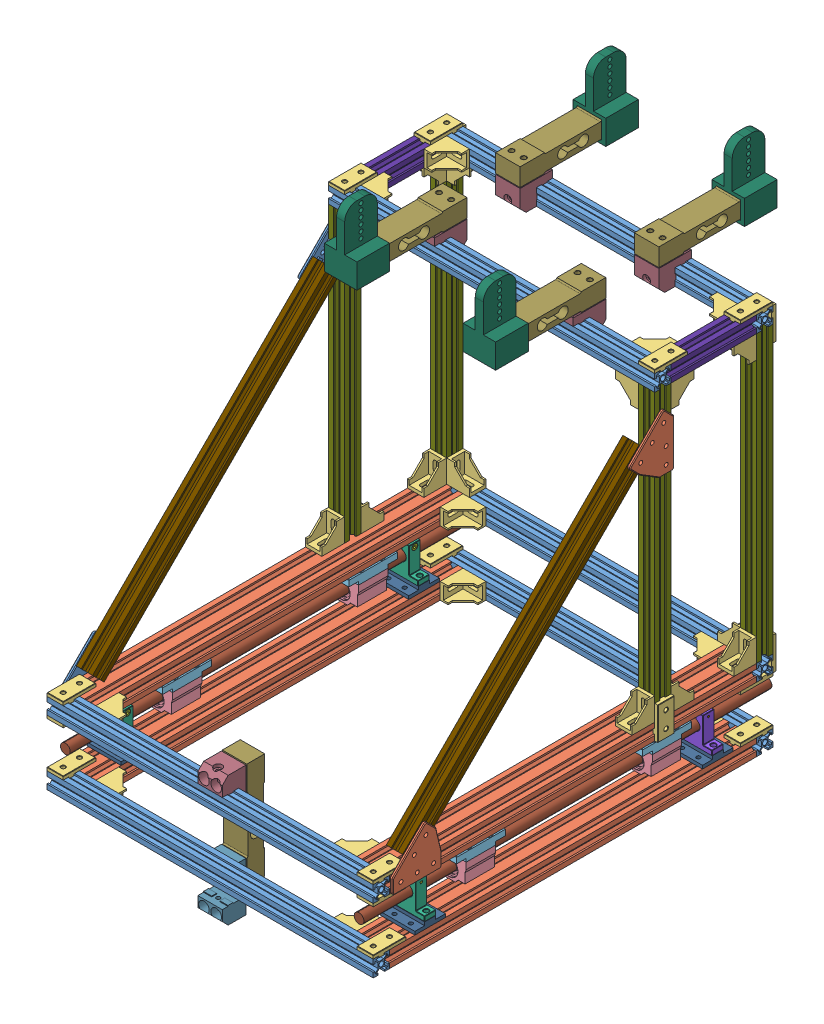
SolidWorks assembly Balança Final, configuration Default. Lengths in mm.
Overall size (408 595 590).
113 component instances, 21 part files, 135 mates.
Components (placement in the parent):
- Quadrado2040-1: Quadrado2040 [Default] at (-124.633 620.1559 -302.6488) x (1 0 0) z (0 -1 0) size (400 490 20)
  - 20x20x400_profile-4: 20x20x400_profile [Default] at (-5.8923 594.8177 297.0396) x (0 1 0) z (0 0 1) size (20 400 20)
  - 20x20x400_profile-5: 20x20x400_profile [Default] at (-405.8923 124.8177 297.0396) x (0 -1 0) z (0 0 1) size (20 400 20)
  - 20x40x450_profile-3: 20x40x450_profile [Default] at (-395.8923 134.8177 297.0396) size (40 450 20)
  - 20x40x450_profile-4: 20x40x450_profile [Default] at (-35.8923 134.8177 297.0396) size (40 450 20)
  - cantoneira_20x20-1: cantoneira_20x20 [Default] at (-45.8923 134.8177 307.0396) x (0 0 -1) z (1 0 0) size (20 28 28)
  - cantoneira_20x20-2: cantoneira_20x20 [Default] at (-45.8923 584.8177 307.0396) x (0 0 -1) z (0 1 0) size (20 28 28)
  - cantoneira_20x20-3: cantoneira_20x20 [Default] at (-365.8923 584.8177 307.0396) x (0 0 -1) z (-1 0 0) size (20 28 28)
  - cantoneira_20x20-4: cantoneira_20x20 [Default] at (-365.8923 134.8177 307.0396) x (0 0 -1) z (0 -1 0) size (20 28 28)
- Quadrado2040-2: Quadrado2040 [Default] at (-124.633 699.1559 -302.6488) x (1 0 0) z (0 -1 0) size (400 490 20)
  - 20x20x400_profile-4: 20x20x400_profile [Default] at (-5.8923 594.8177 297.0396) x (0 1 0) z (0 0 1) size (20 400 20)
  - 20x20x400_profile-5: 20x20x400_profile [Default] at (-405.8923 124.8177 297.0396) x (0 -1 0) z (0 0 1) size (20 400 20)
  - 20x40x450_profile-3: 20x40x450_profile [Default] at (-395.8923 134.8177 297.0396) size (40 450 20)
  - 20x40x450_profile-4: 20x40x450_profile [Default] at (-35.8923 134.8177 297.0396) size (40 450 20)
  - cantoneira_20x20-1: cantoneira_20x20 [Default] at (-45.8923 134.8177 307.0396) x (0 0 -1) z (1 0 0) size (20 28 28)
  - cantoneira_20x20-2: cantoneira_20x20 [Default] at (-45.8923 584.8177 307.0396) x (0 0 -1) z (0 1 0) size (20 28 28)
  - cantoneira_20x20-3: cantoneira_20x20 [Default] at (-365.8923 584.8177 307.0396) x (0 0 -1) z (-1 0 0) size (20 28 28)
  - cantoneira_20x20-4: cantoneira_20x20 [Default] at (-365.8923 134.8177 307.0396) x (0 0 -1) z (0 -1 0) size (20 28 28)
- SC12UU-4: SC12UU [Default] at (-510.5253 380.1163 171.1914) size (42 28 36)
- AdaptadorPillowBlock12-1: AdaptadorPillowBlock12 [Valor predeterminado] at (-510.5253 384.1163 171.1914) x (0 0 -1) z (1 0 0) size (60 12.59 42.39)
- SK12-5: SK12 [Valor predeterminado] at (-504.83 359.1 -160.831) size (42 37.6 14)
  - Shaft support SK12-1: Shaft support SK12 [Valor predeterminado] at (-5.6953 6.0163 42) size (42 37.5 14)
  - m4x16-2: m4x16 [Valor predeterminado] at (4.3047 16.0441 42) x (-1 0 0) z (0 0.924225 0.381849) size (20 7 7)
- EspelharSK12-10: EspelharSK12 [Valor predeterminado] at (-156.2206 359.1 -160.831) x (-1 0 0) z (0 0 -1) size (42 37.6 14)
  - EspelharShaft support SK12-1: EspelharShaft support SK12 [Valor predeterminado] at (-5.6953 6.0163 -42) size (42 37.5 14)
  - Espelharm4x16-1: Espelharm4x16 [Valor predeterminado] at (4.3047 16.0441 -42) x (-1 0 0) z (0 -0.924225 0.381849) size (20 7 7)
- SK12-9: SK12 [Valor predeterminado] at (-504.83 359.1 191.169) size (42 37.6 14)
  - Shaft support SK12-1: Shaft support SK12 [Valor predeterminado] at (-5.6953 6.0163 42) size (42 37.5 14)
  - m4x16-2: m4x16 [Valor predeterminado] at (4.3047 16.0441 42) x (-1 0 0) z (0 0.924225 0.381849) size (20 7 7)
- SK12-11: SK12 [Valor predeterminado] at (-156.2206 359.1 275.169) x (-1 0 0) z (0 0 -1) size (42 37.6 14)
  - Shaft support SK12-1: Shaft support SK12 [Valor predeterminado] at (-5.6953 6.0163 42) size (42 37.5 14)
  - m4x16-2: m4x16 [Valor predeterminado] at (4.3047 16.0441 42) x (-1 0 0) z (0 0.924225 0.381849) size (20 7 7)
- AdaptadorSuporteSK12-1: AdaptadorSuporteSK12 [Valor predeterminado] at (-510.5253 333.1163 -119.081) x (0 0 1) z (-1 0 0) size (37.5 9 42)
- EixoLinear12x500mm-1: EixoLinear12x500mm [Default] at (-510.5253 365.1163 49.5418) x (-0.052176 0.998638 0) z (0 0 1) size (12 12 500)
- EixoLinear12x500mm-2: EixoLinear12x500mm [Default] at (-150.5253 365.1163 49.5418) x (0.95426 0.298977 0) z (0 0 1) size (12 12 500)
- load_cell_big_20kg-9: load_cell_big_20kg [Default] at (-430.5253 803.1163 -212.831) size (30 22 130)
- load_cell_big_20kg-10: load_cell_big_20kg [Default] at (-430.5253 803.1163 -17.831) size (30 22 130)
- SuporteCelulaCarga_Reforcado-1: SuporteCelulaCarga_Reforcado [Valor predeterminado] at (-430.5253 779.361 -166.5879) size (30 30 40)
- SuporteCelulaCarga_Reforcado-2: SuporteCelulaCarga_Reforcado [Valor predeterminado] at (-400.5253 779.361 -64.0742) x (-1 0 0) z (0 0 -1) size (30 30 40)
- SuporteCelulaCarga_Reforcado-6: SuporteCelulaCarga_Reforcado [Valor predeterminado] at (-345.5253 413.3595 284.9243) x (1 0 0) z (0 1 0) size (30 30 40)
- load_cell_big_20kg-1: load_cell_big_20kg [Default] at (-345.5253 367.6163 261.169) x (1 0 0) z (0 -1 0) size (30 22 130)
- SuporteCelulaCarga_Reforcado_Ajustavel-1: SuporteCelulaCarga_Reforcado_Ajustavel [Valor predeterminado] at (-315.5253 291.8731 284.9243) x (-1 0 0) z (0 -1 0) size (30 30 60)
- EncaixeAsaTraseiro_Alt3-1: EncaixeAsaTraseiro_Alt3 [Default] at (-415.5253 788.1163 37.169) size (40 80 40)
- EncaixeAsaTraseiro_Alt3-2: EncaixeAsaTraseiro_Alt3 [Default] at (-415.5253 788.1163 -267.831) x (-1 0 0) z (0 0 -1) size (40 80 40)
- load_cell_big_20kg-11: load_cell_big_20kg [Default] at (-230.5253 803.1163 -212.831) x (-1 0 0) z (0 0 -1) size (30 22 130)
- load_cell_big_20kg-12: load_cell_big_20kg [Default] at (-230.5253 803.1163 -17.831) x (-1 0 0) z (0 0 -1) size (30 22 130)
- EncaixeAsaTraseiro_Alt3-3: EncaixeAsaTraseiro_Alt3 [Default] at (-245.5253 788.1163 -267.831) x (-1 0 0) z (0 0 -1) size (40 80 40)
- EncaixeAsaTraseiro_Alt3-4: EncaixeAsaTraseiro_Alt3 [Default] at (-245.5253 788.1163 37.169) size (40 80 40)
- cantoneira_20x20-1: cantoneira_20x20 [Default] at (-510.5253 412.1163 -167.831) x (-1 0 0) z (0 0 -1) size (20 28 28)
- cantoneira_20x20-2: cantoneira_20x20 [Default] at (-510.5253 412.1163 -187.831) x (0 0 1) z (-1 0 0) size (20 28 28)
- cantoneira_20x20-4: cantoneira_20x20 [Default] at (-530.5253 762.1163 -167.831) x (1 0 0) z (0 0 -1) size (20 28 28)
- cantoneira_20x20-5: cantoneira_20x20 [Default] at (-510.5253 762.1163 -167.831) x (0 0 -1) z (-1 0 0) size (20 28 28)
- cantoneira_20x20-6: cantoneira_20x20 [Default] at (-510.5253 762.1163 -167.831) x (0 1 0) z (0 0 -1) size (20 28 28)
- cantoneira_20x20-7: cantoneira_20x20 [Default] at (-510.5253 762.1163 -62.831) x (0 1 0) z (-1 0 0) size (20 28 28)
- cantoneira_20x20-15: cantoneira_20x20 [Default] at (-530.5253 762.1163 -62.831) x (1 0 0) z (0 1 0) size (20 28 28)
- cantoneira_20x20-16: cantoneira_20x20 [Default] at (-510.5253 762.1163 -42.831) x (0 0 -1) z (-1 0 0) size (20 28 28)
- cantoneira_20x20-21: cantoneira_20x20 [Default] at (-530.5253 412.1163 -62.831) size (20 28 28)
- cantoneira_20x20-23: cantoneira_20x20 [Default] at (-530.5253 412.1163 -42.831) x (1 0 0) z (0 -1 0) size (20 28 28)
- cantoneira_20x20-8: cantoneira_20x20 [Default] at (-130.5253 412.1163 -167.831) x (-1 0 0) z (0 0 -1) size (20 28 28)
- cantoneira_20x20-10: cantoneira_20x20 [Default] at (-150.5253 412.1163 -167.831) x (0 0 -1) z (1 0 0) size (20 28 28)
- cantoneira_20x20-11: cantoneira_20x20 [Default] at (-150.5253 782.1163 -167.831) x (0 -1 0) z (0 0 -1) size (20 28 28)
- cantoneira_20x20-12: cantoneira_20x20 [Default] at (-150.5253 762.1163 -187.831) x (0 0 1) z (1 0 0) size (20 28 28)
- cantoneira_20x20-13: cantoneira_20x20 [Default] at (-150.5253 762.1163 -167.831) x (1 0 0) z (0 0 -1) size (20 28 28)
- cantoneira_20x20-14: cantoneira_20x20 [Default] at (-150.5253 782.1163 -62.831) x (0 -1 0) z (1 0 0) size (20 28 28)
- 20x20x350_profile-7: 20x20x350_profile [Default] at (-520.5253 412.1163 -177.831) size (20 350 20)
- 20x20x350_profile-8: 20x20x350_profile [Default] at (-140.5253 412.1163 -177.831) x (-1 0 0) z (0 0 -1) size (20 350 20)
- 20x20x105_profile-1: 20x20x105_profile [Default] at (-520.5253 772.1163 -167.831) x (1 0 0) z (0 -1 0) size (20 105 20)
- 20x20x105_profile-2: 20x20x105_profile [Default] at (-140.5253 772.1163 -167.831) x (-1 0 0) z (0 1 0) size (20 105 20)
- 20x20x410_profile-1: 20x20x410_profile [Default] at (-520.5253 427.7919 250.4913) x (1 0 0) z (0 0.707107 0.707107) size (20 410 20)
- 20x20x410_profile-2: 20x20x410_profile [Default] at (-140.5253 427.7919 250.4913) x (-1 0 0) z (0 -0.707107 -0.707107) size (20 410 20)
- 20x20x400_profile-1: 20x20x400_profile [Default] at (-130.5253 772.1163 -177.831) x (0 1 0) z (0 0 1) size (20 400 20)
- 20x20x400_profile-2: 20x20x400_profile [Default] at (-130.5253 772.1163 -52.831) x (0 1 0) z (0 0 1) size (20 400 20)
- 20x20x350_profile-9: 20x20x350_profile [Default] at (-520.5253 412.1163 -52.831) size (20 350 20)
- SC12UU-5: SC12UU [Default] at (-510.5253 380.1163 -56.8535) size (42 28 36)
- SC12UU-6: SC12UU [Default] at (-150.5253 380.1163 171.1914) x (-1 0 0) z (0 0 -1) size (42 28 36)
- SC12UU-7: SC12UU [Default] at (-150.5253 380.1163 -56.8535) x (-1 0 0) z (0 0 -1) size (42 28 36)
- AdaptadorPillowBlock12-2: AdaptadorPillowBlock12 [Valor predeterminado] at (-510.5253 384.1163 -56.8535) x (0 0 1) z (-1 0 0) size (60 12.59 42.39)
- AdaptadorPillowBlock12-3: AdaptadorPillowBlock12 [Valor predeterminado] at (-150.5253 384.1163 171.1914) x (0 0 -1) z (1 0 0) size (60 12.59 42.39)
- AdaptadorPillowBlock12-4: AdaptadorPillowBlock12 [Valor predeterminado] at (-150.5253 384.1163 -56.8535) x (0 0 1) z (-1 0 0) size (60 12.59 42.39)
- AdaptadorSuporteSK12-2: AdaptadorSuporteSK12 [Valor predeterminado] at (-510.5253 333.1163 233.419) x (0 0 -1) z (1 0 0) size (37.5 9 42)
- AdaptadorSuporteSK12-3: AdaptadorSuporteSK12 [Valor predeterminado] at (-150.5253 333.1163 -119.081) x (0 0 1) z (-1 0 0) size (37.5 9 42)
- AdaptadorSuporteSK12-4: AdaptadorSuporteSK12 [Valor predeterminado] at (-150.5253 333.1163 233.419) x (0 0 -1) z (1 0 0) size (37.5 9 42)
- SuporteCelulaCarga_Reforcado-3: SuporteCelulaCarga_Reforcado [Valor predeterminado] at (-260.5253 779.361 -166.5879) size (30 30 40)
- SuporteCelulaCarga_Reforcado-4: SuporteCelulaCarga_Reforcado [Valor predeterminado] at (-230.5253 779.361 -64.0742) x (-1 0 0) z (0 0 -1) size (30 30 40)
- Placa_lateral_45_esq-1: Placa_lateral_45_esq [Default] at (-530.5253 392.1163 300.3091) x (-1 0 0) z (0 0 -1) size (6 57.44 60)
- Placa_lateral_45_esq-2: Placa_lateral_45_esq [Default] at (-530.5253 755.2564 -62.831) x (-1 0 0) z (0 -0.707107 0.707107) size (6 57.44 60)
- Placa_lateral_45_dir-1: Placa_lateral_45_dir [Default] at (-126.5253 392.1163 300.3091) x (-1 0 0) z (0 0 -1) size (6 57.44 60)
- Placa_lateral_45_dir-2: Placa_lateral_45_dir [Default] at (-126.5253 755.2564 -62.831) x (-1 0 0) z (0 -0.707107 0.707107) size (6 57.44 60)
- Cantoneira_plana-1: Cantoneira_plana [Valor predeterminado] at (-520.5253 762.1163 -187.831) x (1 0 0) z (0 1 0) size (20 6 40)
- Cantoneira_plana-2: Cantoneira_plana [Valor predeterminado] at (-520.5253 782.1163 -167.831) x (-1 0 0) z (0 0 -1) size (20 6 40)
- Cantoneira_plana-4: Cantoneira_plana [Valor predeterminado] at (-520.5253 412.1163 -187.831) x (-1 0 0) z (0 -1 0) size (20 6 40)
- Cantoneira_plana-5: Cantoneira_plana [Valor predeterminado] at (-520.5253 392.1163 -167.831) x (1 0 0) z (0 0 -1) size (20 6 40)
- Cantoneira_plana-6: Cantoneira_plana [Valor predeterminado] at (-520.5253 392.1163 282.169) x (-1 0 0) z (0 0 1) size (20 6 40)
- Cantoneira_plana-12: Cantoneira_plana [Valor predeterminado] at (-520.5253 782.1163 -62.831) size (20 6 40)
- Cantoneira_plana-14: Cantoneira_plana [Valor predeterminado] at (-520.5253 412.1163 282.169) size (20 6 40)
- Cantoneira_plana-18: Cantoneira_plana [Valor predeterminado] at (-520.5253 333.1163 -167.831) x (-1 0 0) z (0 0 -1) size (20 6 40)
- Cantoneira_plana-19: Cantoneira_plana [Valor predeterminado] at (-520.5253 333.1163 282.169) size (20 6 40)
- Cantoneira_plana-22: Cantoneira_plana [Valor predeterminado] at (-530.5253 412.1163 -52.831) x (0 0 1) z (0 -1 0) size (20 6 40)
- Cantoneira_plana-7: Cantoneira_plana [Valor predeterminado] at (-140.5253 392.1163 -167.831) x (1 0 0) z (0 0 -1) size (20 6 40)
- Cantoneira_plana-8: Cantoneira_plana [Valor predeterminado] at (-140.5253 412.1163 -187.831) x (-1 0 0) z (0 -1 0) size (20 6 40)
- Cantoneira_plana-9: Cantoneira_plana [Valor predeterminado] at (-140.5253 392.1163 282.169) x (-1 0 0) z (0 0 1) size (20 6 40)
- Cantoneira_plana-10: Cantoneira_plana [Valor predeterminado] at (-140.5253 762.1163 -187.831) x (1 0 0) z (0 1 0) size (20 6 40)
- Cantoneira_plana-11: Cantoneira_plana [Valor predeterminado] at (-140.5253 782.1163 -167.831) x (-1 0 0) z (0 0 -1) size (20 6 40)
- Cantoneira_plana-13: Cantoneira_plana [Valor predeterminado] at (-140.5253 782.1163 -62.831) size (20 6 40)
- Cantoneira_plana-15: Cantoneira_plana [Valor predeterminado] at (-140.5253 412.1163 282.169) size (20 6 40)
- Cantoneira_plana-20: Cantoneira_plana [Valor predeterminado] at (-140.5253 333.1163 -167.831) x (-1 0 0) z (0 0 -1) size (20 6 40)
- Cantoneira_plana-21: Cantoneira_plana [Valor predeterminado] at (-140.5253 333.1163 282.169) size (20 6 40)
- cantoneira_20x20-19: cantoneira_20x20 [Default] at (-150.5253 762.1163 -62.831) x (1 0 0) z (0 1 0) size (20 28 28)
- cantoneira_20x20-20: cantoneira_20x20 [Default] at (-150.5253 762.1163 -62.831) x (0 0 1) z (1 0 0) size (20 28 28)
- cantoneira_20x20-22: cantoneira_20x20 [Default] at (-150.5253 412.1163 -62.831) size (20 28 28)
- cantoneira_20x20-24: cantoneira_20x20 [Default] at (-150.5253 412.1163 -42.831) x (1 0 0) z (0 -1 0) size (20 28 28)
- 20x20x350_profile-11: 20x20x350_profile [Default] at (-140.5253 412.1163 -52.831) x (-1 0 0) z (0 0 -1) size (20 350 20)
- Cantoneira_plana-24: Cantoneira_plana [Valor predeterminado] at (-130.5253 412.1163 -52.831) x (0 0 -1) z (0 -1 0) size (20 6 40)
Mates (geometry in assembly coordinates):
- Concentric1: concentric anti-aligned: cylinder of SK12-9/Shaft support SK12-1 through (-510.5253 365.1163 226.169) axis (0 0 1) radius 6; cylinder of EixoLinear12x500mm-1 through (-510.5253 365.1163 299.5418) axis (0 0 -1) radius 6
- Concentric2: concentric aligned: cylinder of ? through (-150.5253 356.1163 -143.831) axis (0 0 -1) radius 6; cylinder of EixoLinear12x500mm-2 through (-150.5253 356.1163 312.6848) axis (0 0 -1) radius 6
- Concentric4: concentric anti-aligned: cylinder of EixoLinear12x500mm-1 through (-510.5253 365.1163 299.5418) axis (0 0 -1) radius 6; cylinder of SC12UU-4 through (-510.5253 365.1163 201.4668) axis (0 0 1) radius 6
- Coincident15: coincident aligned: plane of Quadrado2040-1/20x20x400_profile-4 through (-530.5253 319.1163 302.169) normal (0 0 1); plane of Quadrado2040-2/20x20x400_profile-4 through (-530.5253 398.1163 302.169) normal (0 0 1)
- Coincident16: coincident aligned: plane of Quadrado2040-1/20x40x450_profile-3 through (-530.5253 333.1163 282.169) normal (-1 0 0); plane of Quadrado2040-2/20x40x450_profile-3 through (-530.5253 412.1163 282.169) normal (-1 0 0)
- Width6: width anti-aligned: plane of load_cell_big_20kg-1 through (-345.5253 367.6163 261.169) normal (-1 0 0); plane of load_cell_big_20kg-1 through (-315.5253 367.6163 261.169) normal (1 0 0); plane of Quadrado2040-2/20x20x400_profile-4 through (-130.5253 402.1163 292.169) normal (1 0 0); plane of Quadrado2040-2/20x20x400_profile-4 through (-530.5253 402.1163 292.169) normal (-1 0 0)
- Coincident124: coincident aligned: plane of 20x20x350_profile-7 through (-530.5253 762.1163 -173.831) normal (-1 0 0); plane of 20x20x105_profile-1 through (-530.5253 782.1163 -62.831) normal (-1 0 0)
- Coincident133: coincident aligned: plane of 20x20x105_profile-1 through (-530.5253 768.1163 -62.831) normal (-1 0 0); plane of 20x20x410_profile-1 through (-530.5253 702.0301 -37.889) normal (-1 0 0)
- Coincident145: coincident anti-aligned: plane of load_cell_big_20kg-10 through (-400.5253 803.1163 47.169) normal (0 0 1); plane of EncaixeAsaTraseiro_Alt3-1 through (-415.5253 788.1163 47.169) normal (0 0 -1)
- Coincident146: coincident anti-aligned: plane of load_cell_big_20kg-10 through (-400.5253 803.1163 -17.831) normal (1 0 0); plane of EncaixeAsaTraseiro_Alt3-1 through (-400.5253 814.1163 47.169) normal (-1 0 0)
- Coincident147: coincident anti-aligned: plane of load_cell_big_20kg-10 through (-400.5253 792.1163 -17.831) normal (0 -1 0); plane of EncaixeAsaTraseiro_Alt3-1 through (-400.5253 792.1163 47.169) normal (0 1 0)
- Coincident150: coincident anti-aligned: plane of load_cell_big_20kg-9 through (-400.5253 792.1163 -212.831) normal (0 -1 0); plane of EncaixeAsaTraseiro_Alt3-2 through (-430.5253 792.1163 -277.831) normal (0 1 0)
- Coincident151: coincident anti-aligned: plane of load_cell_big_20kg-9 through (-400.5253 803.1163 -277.831) normal (0 0 -1); plane of EncaixeAsaTraseiro_Alt3-2 through (-415.5253 788.1163 -277.831) normal (0 0 1)
- Coincident152: coincident anti-aligned: plane of load_cell_big_20kg-9 through (-430.5253 803.1163 -212.831) normal (-1 0 0); plane of EncaixeAsaTraseiro_Alt3-2 through (-430.5253 814.1163 -277.831) normal (1 0 0)
- Coincident174: coincident anti-aligned: plane of Quadrado2040-2/20x20x400_profile-5 through (-130.5253 412.1163 -167.831) normal (0 1 0); plane of 20x20x350_profile-7 through (-520.5253 412.1163 -177.831) normal (0 -1 0)
- Coincident178: coincident aligned: plane of Quadrado2040-2/20x20x400_profile-5 through (-130.5253 398.1163 -187.831) normal (0 0 -1); plane of 20x20x350_profile-8 through (-130.5253 762.1163 -187.831) normal (0 0 -1)
- Coincident194: coincident aligned: plane of EixoLinear12x500mm-1 through (-510.5253 365.1163 -200.4582) normal (0 0 -1); plane of EixoLinear12x500mm-2 through (-150.5253 365.1163 -200.4582) normal (0 0 -1)
- Coincident197: coincident: plane of Quadrado2040-2/20x40x450_profile-3 through (-530.5253 412.1163 282.169) normal (0 1 0); line of 20x20x410_profile-1 through (-530.5253 412.1163 252.0248) axis (1 0 0)
- Coincident199: coincident anti-aligned: plane of Quadrado2040-2/20x40x450_profile-3 through (-530.5253 412.1163 282.169) normal (0 1 0); plane of cantoneira_20x20-1 through (-530.5253 412.1163 -167.831) normal (0 -1 0)
- Coincident200: coincident aligned: plane of Quadrado2040-2/20x40x450_profile-3 through (-530.5253 412.1163 282.169) normal (-1 0 0); plane of cantoneira_20x20-1 through (-530.5253 412.1163 -167.831) normal (-1 0 0)
- Coincident201: coincident anti-aligned: plane of 20x20x350_profile-7 through (-530.5253 762.1163 -167.831) normal (0 0 1); plane of cantoneira_20x20-1 through (-530.5253 412.1163 -167.831) normal (0 0 -1)
- Coincident202: coincident anti-aligned: plane of 20x20x350_profile-7 through (-510.5253 762.1163 -187.831) normal (1 0 0); plane of cantoneira_20x20-2 through (-510.5253 412.1163 -167.831) normal (-1 0 0)
- Coincident203: coincident anti-aligned: plane of Quadrado2040-2/20x20x400_profile-5 through (-130.5253 412.1163 -181.831) normal (0 1 0); plane of cantoneira_20x20-2 through (-510.5253 412.1163 -167.831) normal (0 -1 0)
- Coincident204: coincident aligned: plane of Quadrado2040-2/20x20x400_profile-5 through (-130.5253 412.1163 -187.831) normal (0 0 -1); plane of cantoneira_20x20-2 through (-510.5253 412.1163 -187.831) normal (0 0 -1)
- Coincident211: coincident anti-aligned: plane of 20x20x105_profile-1 through (-510.5253 782.1163 -62.831) normal (1 0 0); plane of cantoneira_20x20-6 through (-510.5253 782.1163 -167.831) normal (-1 0 0)
- Coincident213: coincident aligned: plane of 20x20x105_profile-1 through (-530.5253 768.1163 -62.831) normal (-1 0 0); plane of cantoneira_20x20-4 through (-530.5253 762.1163 -167.831) normal (-1 0 0)
- Coincident214: coincident anti-aligned: plane of 20x20x350_profile-7 through (-530.5253 762.1163 -167.831) normal (0 0 1); plane of cantoneira_20x20-4 through (-510.5253 762.1163 -167.831) normal (0 0 -1)
- Coincident215: coincident anti-aligned: plane of 20x20x105_profile-1 through (-530.5253 762.1163 -62.831) normal (0 -1 0); plane of cantoneira_20x20-4 through (-510.5253 762.1163 -167.831) normal (0 1 0)
- Coincident216: coincident anti-aligned: plane of 20x20x350_profile-7 through (-510.5253 762.1163 -173.831) normal (1 0 0); plane of cantoneira_20x20-5 through (-510.5253 762.1163 -187.831) normal (-1 0 0)
- Coincident220: coincident anti-aligned: plane of 20x20x105_profile-1 through (-510.5253 782.1163 -62.831) normal (1 0 0); plane of cantoneira_20x20-7 through (-510.5253 782.1163 -62.831) normal (-1 0 0)
- Coincident222: coincident aligned: plane of 20x20x105_profile-1 through (-516.5253 782.1163 -62.831) normal (0 1 0); plane of cantoneira_20x20-7 through (-510.5253 782.1163 -62.831) normal (0 1 0)
- Coincidente1: coincident aligned: plane of 20x20x350_profile-7 through (-530.5253 762.1163 -187.831) normal (-1 0 0); plane of 20x20x400_profile-1 through (-530.5253 772.1163 -177.831) normal (-1 0 0)
- Coincidente2: coincident aligned: plane of 20x20x350_profile-7 through (-516.5253 762.1163 -187.831) normal (0 0 -1); plane of 20x20x400_profile-1 through (-530.5253 776.1163 -187.831) normal (0 0 -1)
- Coincidente3: coincident anti-aligned: plane of 20x20x350_profile-7 through (-520.5253 762.1163 -177.831) normal (0 1 0); plane of 20x20x400_profile-1 through (-530.5253 762.1163 -187.831) normal (0 -1 0)
- Coincidente4: coincident anti-aligned: plane of 20x20x105_profile-1 through (-520.5253 772.1163 -167.831) normal (0 0 -1); plane of 20x20x400_profile-1 through (-530.5253 776.1163 -167.831) normal (0 0 1)
- Coincidente7: coincident aligned: plane of 20x20x105_profile-1 through (-530.5253 782.1163 -62.831) normal (-1 0 0); plane of 20x20x400_profile-2 through (-530.5253 772.1163 -52.831) normal (-1 0 0)
- Coincidente8: coincident aligned: plane of 20x20x105_profile-1 through (-516.5253 782.1163 -62.831) normal (0 1 0); plane of 20x20x400_profile-2 through (-530.5253 782.1163 -62.831) normal (0 1 0)
- Coincidente9: coincident aligned: plane of 20x20x105_profile-1 through (-516.5253 782.1163 -62.831) normal (0 1 0); plane of 20x20x400_profile-1 through (-530.5253 782.1163 -173.831) normal (0 1 0)
- Coincidente10: coincident anti-aligned: plane of 20x20x105_profile-1 through (-520.5253 772.1163 -62.831) normal (0 0 1); plane of 20x20x400_profile-2 through (-530.5253 762.1163 -62.831) normal (0 0 -1)
- Distância1: distance = 100 mm aligned: plane of load_cell_big_20kg-9 through (-430.5253 803.1163 -212.831) normal (-1 0 0); plane of 20x20x400_profile-1 through (-530.5253 772.1163 -177.831) normal (-1 0 0)
- Coincidente21: coincident aligned: plane of load_cell_big_20kg-9 through (-430.5253 803.1163 -212.831) normal (-1 0 0); plane of load_cell_big_20kg-10 through (-430.5253 803.1163 -17.831) normal (-1 0 0)
- Concêntrico1: concentric anti-aligned: cylinder of EspelharSK12-10/EspelharShaft support SK12-1 through (-150.5253 365.1163 -125.831) axis (0 0 1) radius 6; cylinder of EixoLinear12x500mm-2 through (-150.5253 365.1163 299.5418) axis (0 0 -1) radius 6
- Coincidente22: coincident anti-aligned: plane of Quadrado2040-2/20x40x450_profile-3 through (-516.5253 392.1163 282.169) normal (0 -1 0); plane of AdaptadorPillowBlock12-1 through (-510.5253 392.1163 171.1914) normal (0 1 0)
- Coincidente23: coincident anti-aligned: plane of SC12UU-4 through (-521.5253 380.1163 189.1914) normal (0 1 0); plane of AdaptadorPillowBlock12-1 through (-510.5253 380.1163 171.1914) normal (0 -1 0)
- Coincidente24: coincident aligned: plane of SC12UU-4 through (-531.5253 380.1163 189.1914) normal (-1 0 0); plane of AdaptadorPillowBlock12-1 through (-531.5253 392.1163 171.1914) normal (-1 0 0)
- Coincidente25: coincident aligned: plane of SC12UU-4 through (-510.5253 380.1163 153.1914) normal (0 0 -1); plane of AdaptadorPillowBlock12-1 through (-510.5253 380.1163 153.1914) normal (0 0 -1)
- Distância2: distance = 1 mm aligned: plane of AdaptadorPillowBlock12-1 through (-531.5253 392.1163 171.1914) normal (-1 0 0); plane of Quadrado2040-2/20x40x450_profile-3 through (-530.5253 398.1163 282.169) normal (-1 0 0)
- Concêntrico2: concentric anti-aligned: cylinder of SK12-5/Shaft support SK12-1 through (-510.5253 365.1163 -125.831) axis (0 0 1) radius 6; cylinder of EixoLinear12x500mm-1 through (-510.5253 365.1163 299.5418) axis (0 0 -1) radius 6
- Coincidente32: coincident anti-aligned: plane of cantoneira_20x20-5 through (-510.5253 762.1163 -187.831) normal (0 1 0); plane of 20x20x400_profile-1 through (-530.5253 762.1163 -187.831) normal (0 -1 0)
- Coincidente33: coincident aligned: plane of cantoneira_20x20-5 through (-510.5253 762.1163 -187.831) normal (0 0 -1); plane of 20x20x400_profile-1 through (-530.5253 762.1163 -187.831) normal (0 0 -1)
- Coincidente34: coincident anti-aligned: plane of 20x20x105_profile-1 through (-510.5253 782.1163 -62.831) normal (1 0 0); plane of cantoneira_20x20-6 through (-510.5253 782.1163 -167.831) normal (-1 0 0)
- Coincidente35: coincident aligned: plane of cantoneira_20x20-6 through (-510.5253 782.1163 -167.831) normal (0 1 0); plane of 20x20x400_profile-1 through (-530.5253 782.1163 -173.831) normal (0 1 0)
- Coincidente36: coincident anti-aligned: plane of cantoneira_20x20-6 through (-510.5253 782.1163 -167.831) normal (0 0 -1); plane of 20x20x400_profile-1 through (-530.5253 776.1163 -167.831) normal (0 0 1)
- Coincidente37: coincident anti-aligned: plane of Quadrado2040-1/20x40x450_profile-3 through (-530.5253 333.1163 282.169) normal (0 1 0); plane of AdaptadorSuporteSK12-1 through (-510.5253 333.1163 -119.081) normal (0 -1 0)
- Coincidente40: coincident anti-aligned: plane of SK12-5/Shaft support SK12-1 through (-510.5253 342.1163 -125.831) normal (0 -1 0); plane of AdaptadorSuporteSK12-1 through (-510.5253 342.1163 -119.081) normal (0 1 0)
- Coincidente41: coincident aligned: plane of SK12-5/Shaft support SK12-1 through (-510.5253 316.9299 -125.831) normal (0 0 -1); plane of AdaptadorSuporteSK12-1 through (-510.5253 342.1163 -125.831) normal (0 0 -1)
- Coincidente42: coincident aligned: plane of SK12-5/Shaft support SK12-1 through (-531.5253 316.9299 -125.831) normal (-1 0 0); plane of AdaptadorSuporteSK12-1 through (-531.5253 338.1163 -119.081) normal (-1 0 0)
- Coincidente44: coincident anti-aligned: plane of 20x20x400_profile-1 through (-530.5253 782.1163 -173.831) normal (0 1 0); plane of SuporteCelulaCarga_Reforcado-1 through (-400.5253 782.1163 -166.5879) normal (0 -1 0)
- Coincidente45: coincident anti-aligned: plane of 20x20x400_profile-1 through (-530.5253 776.1163 -167.831) normal (0 0 1); plane of SuporteCelulaCarga_Reforcado-1 through (-400.5253 779.361 -167.831) normal (0 0 -1)
- Coincidente46: coincident aligned: plane of load_cell_big_20kg-9 through (-400.5253 803.1163 -147.831) normal (0 0 1); plane of SuporteCelulaCarga_Reforcado-1 through (-400.5253 779.361 -147.831) normal (0 0 1)
- Coincidente47: coincident anti-aligned: plane of load_cell_big_20kg-9 through (-400.5253 792.1163 -212.831) normal (0 -1 0); plane of SuporteCelulaCarga_Reforcado-1 through (-400.5253 792.1163 -166.5879) normal (0 1 0)
- Coincidente48: coincident aligned: plane of load_cell_big_20kg-9 through (-430.5253 803.1163 -212.831) normal (-1 0 0); plane of SuporteCelulaCarga_Reforcado-1 through (-430.5253 779.361 -166.5879) normal (-1 0 0)
- Coincidente49: coincident anti-aligned: plane of 20x20x400_profile-2 through (-530.5253 782.1163 -48.831) normal (0 1 0); plane of SuporteCelulaCarga_Reforcado-2 through (-430.5253 782.1163 -64.0742) normal (0 -1 0)
- Coincidente50: coincident anti-aligned: plane of 20x20x400_profile-2 through (-530.5253 776.1163 -62.831) normal (0 0 -1); plane of SuporteCelulaCarga_Reforcado-2 through (-430.5253 779.361 -62.831) normal (0 0 1)
- Coincidente51: coincident aligned: plane of load_cell_big_20kg-10 through (-430.5253 803.1163 -17.831) normal (-1 0 0); plane of SuporteCelulaCarga_Reforcado-2 through (-430.5253 779.361 -64.0742) normal (-1 0 0)
- Coincidente52: coincident aligned: plane of load_cell_big_20kg-10 through (-400.5253 803.1163 -82.831) normal (0 0 -1); plane of SuporteCelulaCarga_Reforcado-2 through (-430.5253 779.361 -82.831) normal (0 0 -1)
- Coincidente53: coincident anti-aligned: plane of load_cell_big_20kg-10 through (-400.5253 792.1163 -17.831) normal (0 -1 0); plane of SuporteCelulaCarga_Reforcado-2 through (-430.5253 792.1163 -64.0742) normal (0 1 0)
- Coincidente55: coincident anti-aligned: plane of Quadrado2040-2/20x20x400_profile-4 through (-530.5253 398.1163 282.169) normal (0 0 -1); plane of SuporteCelulaCarga_Reforcado-6 through (-315.5253 413.3595 282.169) normal (0 0 1)
- Largura2: width anti-aligned: plane of SuporteCelulaCarga_Reforcado-6 through (-315.5253 413.3595 284.9243) normal (1 0 0); plane of SuporteCelulaCarga_Reforcado-6 through (-345.5253 413.3595 284.9243) normal (-1 0 0); plane of Quadrado2040-2/20x20x400_profile-4 through (-130.5253 402.1163 292.169) normal (1 0 0); plane of Quadrado2040-2/20x20x400_profile-4 through (-530.5253 402.1163 292.169) normal (-1 0 0)
- Coincidente60: coincident anti-aligned: plane of load_cell_big_20kg-1 through (-315.5253 367.6163 272.169) normal (0 0 1); plane of SuporteCelulaCarga_Reforcado-6 through (-315.5253 413.3595 272.169) normal (0 0 -1)
- Coincidente61: coincident anti-aligned: plane of Quadrado2040-2/20x20x400_profile-4 through (-530.5253 412.1163 296.169) normal (0 1 0); plane of SuporteCelulaCarga_Reforcado-6 through (-315.5253 412.1163 284.9243) normal (0 -1 0)
- Concêntrico3: concentric anti-aligned: cylinder of load_cell_big_20kg-1 through (-338.0253 420.6163 250.169) axis (0 0 1) radius 2.75; cylinder of SuporteCelulaCarga_Reforcado-6 through (-338.0253 420.6163 302.17) axis (0 0 -1) radius 3.25
- Coincidente63: coincident anti-aligned: plane of Quadrado2040-2/20x40x450_profile-3 through (-530.5253 412.1163 282.169) normal (-1 0 0); plane of Placa_lateral_45_esq-1 through (-530.5253 392.1163 300.3091) normal (1 0 0)
- Coincidente64: coincident aligned: plane of 20x20x410_profile-1 through (-530.5253 716.1722 -23.7468) normal (0 0.707107 0.707107); plane of Placa_lateral_45_esq-1 through (-534.5253 410.2564 282.169) normal (0 0.707107 0.707107)
- Coincidente65: coincident aligned: plane of Quadrado2040-2/20x40x450_profile-3 through (-530.5253 392.1163 282.169) normal (0 -1 0); plane of Placa_lateral_45_esq-1 through (-534.5253 392.1163 222.169) normal (0 -1 0)
- Coincidente66: coincident anti-aligned: plane of 20x20x105_profile-1 through (-530.5253 768.1163 -62.831) normal (-1 0 0); plane of Placa_lateral_45_esq-2 through (-530.5253 755.2564 -62.831) normal (1 0 0)
- Coincidente73: coincident anti-aligned: plane of 20x20x410_profile-2 through (-130.5253 706.2727 -33.6463) normal (1 0 0); plane of Placa_lateral_45_dir-2 through (-130.5253 755.2564 -62.831) normal (-1 0 0)
- Coincidente74: coincident anti-aligned: plane of 20x20x410_profile-2 through (-130.5253 706.2727 -33.6463) normal (1 0 0); plane of Placa_lateral_45_dir-1 through (-130.5253 392.1163 300.3091) normal (-1 0 0)
- Coincidente75: coincident aligned: plane of 20x20x410_profile-2 through (-130.5253 716.1722 -23.7468) normal (0 0.707107 0.707107); plane of Placa_lateral_45_dir-1 through (-130.5253 410.2564 282.169) normal (0 0.707107 0.707107)
- Coincidente76: coincident aligned: plane of Quadrado2040-2/20x40x450_profile-4 through (-130.5253 392.1163 282.169) normal (0 -1 0); plane of Placa_lateral_45_dir-1 through (-130.5253 392.1163 222.169) normal (0 -1 0)
- Coincidente78: coincident aligned: plane of 20x20x350_profile-7 through (-530.5253 762.1163 -187.831) normal (-1 0 0); plane of Cantoneira_plana-1 through (-530.5253 742.1163 -191.831) normal (-1 0 0)
- Coincidente79: coincident anti-aligned: plane of 20x20x350_profile-7 through (-530.5253 762.1163 -187.831) normal (0 0 -1); plane of Cantoneira_plana-1 through (-520.5253 762.1163 -187.831) normal (0 0 1)
- Coincidente80: coincident aligned: plane of 20x20x400_profile-1 through (-530.5253 782.1163 -187.831) normal (0 1 0); plane of Cantoneira_plana-1 through (-530.5253 782.1163 -191.831) normal (0 1 0)
- Coincidente83: coincident anti-aligned: plane of 20x20x105_profile-1 through (-530.5253 782.1163 -62.831) normal (0 1 0); plane of Cantoneira_plana-2 through (-520.5253 782.1163 -167.831) normal (0 -1 0)
- Coincidente86: coincident anti-aligned: plane of 20x20x350_profile-7 through (-530.5253 762.1163 -187.831) normal (0 0 -1); plane of Cantoneira_plana-4 through (-520.5253 412.1163 -187.831) normal (0 0 1)
- Coincidente87: coincident anti-aligned: plane of Quadrado2040-2/20x40x450_profile-3 through (-516.5253 392.1163 282.169) normal (0 -1 0); plane of Cantoneira_plana-5 through (-520.5253 392.1163 -167.831) normal (0 1 0)
- Coincidente88: coincident aligned: plane of Quadrado2040-2/20x40x450_profile-3 through (-530.5253 398.1163 282.169) normal (-1 0 0); plane of Cantoneira_plana-5 through (-530.5253 388.1163 -147.831) normal (-1 0 0)
- Coincidente89: coincident aligned: plane of Quadrado2040-2/20x20x400_profile-5 through (-130.5253 412.1163 -187.831) normal (0 0 -1); plane of Cantoneira_plana-5 through (-530.5253 388.1163 -187.831) normal (0 0 -1)
- Coincidente90: coincident aligned: plane of Quadrado2040-2/20x20x400_profile-5 through (-130.5253 392.1163 -181.831) normal (0 -1 0); plane of Cantoneira_plana-4 through (-510.5253 392.1163 -191.831) normal (0 -1 0)
- Coincidente91: coincident aligned: plane of 20x20x350_profile-7 through (-530.5253 762.1163 -187.831) normal (-1 0 0); plane of Cantoneira_plana-4 through (-530.5253 432.1163 -191.831) normal (-1 0 0)
- Coincidente92: coincident aligned: plane of 20x20x400_profile-1 through (-530.5253 776.1163 -187.831) normal (0 0 -1); plane of Cantoneira_plana-2 through (-510.5253 786.1163 -187.831) normal (0 0 -1)
- Coincidente93: coincident aligned: plane of 20x20x105_profile-1 through (-530.5253 782.1163 -62.831) normal (-1 0 0); plane of Cantoneira_plana-2 through (-530.5253 786.1163 -147.831) normal (-1 0 0)
- Coincidente94: coincident aligned: plane of Quadrado2040-2/20x20x400_profile-4 through (-530.5253 398.1163 302.169) normal (0 0 1); plane of Cantoneira_plana-6 through (-510.5253 388.1163 302.169) normal (0 0 1)
- Coincidente95: coincident aligned: plane of Quadrado2040-2/20x40x450_profile-3 through (-530.5253 398.1163 282.169) normal (-1 0 0); plane of Cantoneira_plana-6 through (-530.5253 388.1163 262.169) normal (-1 0 0)
- Coincidente96: coincident anti-aligned: plane of Quadrado2040-2/20x40x450_profile-3 through (-530.5253 392.1163 282.169) normal (0 -1 0); plane of Cantoneira_plana-6 through (-520.5253 392.1163 282.169) normal (0 1 0)
- Coincidente97: coincident aligned: plane of 20x20x400_profile-2 through (-530.5253 776.1163 -42.831) normal (0 0 1); plane of Cantoneira_plana-12 through (-530.5253 786.1163 -42.831) normal (0 0 1)
- Coincidente98: coincident aligned: plane of 20x20x105_profile-1 through (-530.5253 782.1163 -62.831) normal (-1 0 0); plane of Cantoneira_plana-12 through (-530.5253 786.1163 -82.831) normal (-1 0 0)
- Coincidente99: coincident anti-aligned: plane of 20x20x105_profile-1 through (-530.5253 782.1163 -62.831) normal (0 1 0); plane of Cantoneira_plana-12 through (-520.5253 782.1163 -62.831) normal (0 -1 0)
- Coincidente100: coincident aligned: plane of Quadrado2040-2/20x20x400_profile-4 through (-530.5253 412.1163 302.169) normal (0 0 1); plane of Cantoneira_plana-14 through (-530.5253 416.1163 302.169) normal (0 0 1)
- Coincidente101: coincident aligned: plane of Quadrado2040-2/20x40x450_profile-3 through (-530.5253 412.1163 282.169) normal (-1 0 0); plane of Cantoneira_plana-14 through (-530.5253 416.1163 262.169) normal (-1 0 0)
- Coincidente102: coincident anti-aligned: plane of Quadrado2040-2/20x40x450_profile-3 through (-530.5253 412.1163 282.169) normal (0 1 0); plane of Cantoneira_plana-14 through (-520.5253 412.1163 282.169) normal (0 -1 0)
- Distância3: distance = 30 mm: plane of AdaptadorSuporteSK12-1 through (-510.5253 338.1163 -137.831) normal (0 0 -1); line of Quadrado2040-1/20x20x400_profile-5 through (-130.5253 333.1163 -167.831) axis (-1 0 0)
- Coincidente107: coincident aligned: plane of Quadrado2040-1/20x40x450_profile-3 through (-530.5253 333.1163 282.169) normal (-1 0 0); plane of Cantoneira_plana-18 through (-530.5253 337.1163 -147.831) normal (-1 0 0)
- Coincidente108: coincident aligned: plane of Quadrado2040-1/20x20x400_profile-5 through (-130.5253 333.1163 -187.831) normal (0 0 -1); plane of Cantoneira_plana-18 through (-510.5253 337.1163 -187.831) normal (0 0 -1)
- Coincidente109: coincident anti-aligned: plane of Quadrado2040-1/20x40x450_profile-3 through (-530.5253 333.1163 282.169) normal (0 1 0); plane of Cantoneira_plana-18 through (-520.5253 333.1163 -167.831) normal (0 -1 0)
- Coincidente110: coincident aligned: plane of Quadrado2040-1/20x40x450_profile-3 through (-530.5253 333.1163 282.169) normal (-1 0 0); plane of Cantoneira_plana-19 through (-530.5253 337.1163 262.169) normal (-1 0 0)
- Coincidente111: coincident aligned: plane of Quadrado2040-1/20x20x400_profile-4 through (-530.5253 333.1163 302.169) normal (0 0 1); plane of Cantoneira_plana-19 through (-530.5253 337.1163 302.169) normal (0 0 1)
- Coincidente112: coincident anti-aligned: plane of Quadrado2040-1/20x40x450_profile-3 through (-530.5253 333.1163 282.169) normal (0 1 0); plane of Cantoneira_plana-19 through (-520.5253 333.1163 282.169) normal (0 -1 0)
- Coincidente113: coincident aligned: plane of 20x20x105_profile-2 through (-130.5253 776.1163 -62.831) normal (1 0 0); plane of 20x20x400_profile-1 through (-130.5253 772.1163 -177.831) normal (1 0 0)
- Coincidente114: coincident aligned: plane of 20x20x400_profile-2 through (-530.5253 772.1163 -52.831) normal (-1 0 0); plane of 20x20x350_profile-9 through (-530.5253 762.1163 -62.831) normal (-1 0 0)
- Coincidente115: coincident aligned: plane of 20x20x400_profile-2 through (-530.5253 776.1163 -42.831) normal (0 0 1); plane of 20x20x350_profile-9 through (-530.5253 762.1163 -42.831) normal (0 0 1)
- Coincidente116: coincident anti-aligned: plane of 20x20x400_profile-2 through (-530.5253 762.1163 -62.831) normal (0 -1 0); plane of 20x20x350_profile-9 through (-520.5253 762.1163 -52.831) normal (0 1 0)
- Coincidente117: coincident aligned: plane of 20x20x410_profile-1 through (-530.5253 716.1722 -23.7468) normal (0 0.707107 0.707107); plane of Placa_lateral_45_esq-2 through (-534.5253 700.003 -7.5776) normal (0 0.707107 0.707107)
- Coincidente118: coincident aligned: plane of Placa_lateral_45_esq-2 through (-534.5253 729.6024 -62.831) normal (0 0 -1); plane of 20x20x350_profile-9 through (-530.5253 762.1163 -62.831) normal (0 0 -1)
- Coincidente119: coincident aligned: plane of 20x20x410_profile-2 through (-130.5253 716.1722 -23.7468) normal (0 0.707107 0.707107); plane of Placa_lateral_45_dir-2 through (-130.5253 700.003 -7.5776) normal (0 0.707107 0.707107)
- Coincidente125: coincident anti-aligned: plane of Quadrado2040-2/20x20x400_profile-4 through (-530.5253 398.1163 282.169) normal (0 0 -1); plane of Placa_lateral_45_esq-1 through (-534.5253 392.1163 282.169) normal (0 0 1)
- Coincidente126: coincident anti-aligned: plane of Quadrado2040-2/20x20x400_profile-4 through (-530.5253 398.1163 282.169) normal (0 0 -1); plane of Placa_lateral_45_dir-1 through (-130.5253 392.1163 282.169) normal (0 0 1)
- Coincidente128: coincident anti-aligned: plane of cantoneira_20x20-7 through (-510.5253 782.1163 -62.831) normal (0 0 1); plane of 20x20x400_profile-2 through (-530.5253 776.1163 -62.831) normal (0 0 -1)
- Coincidente129: coincident aligned: plane of 20x20x350_profile-9 through (-530.5253 762.1163 -62.831) normal (-1 0 0); plane of cantoneira_20x20-15 through (-530.5253 762.1163 -62.831) normal (-1 0 0)
- Coincidente130: coincident anti-aligned: plane of 20x20x105_profile-1 through (-530.5253 762.1163 -62.831) normal (0 -1 0); plane of cantoneira_20x20-15 through (-510.5253 762.1163 -62.831) normal (0 1 0)
- Coincidente131: coincident anti-aligned: plane of 20x20x350_profile-9 through (-530.5253 762.1163 -62.831) normal (0 0 -1); plane of cantoneira_20x20-15 through (-510.5253 762.1163 -62.831) normal (0 0 1)
- Coincidente132: coincident anti-aligned: plane of 20x20x400_profile-2 through (-530.5253 762.1163 -62.831) normal (0 -1 0); plane of cantoneira_20x20-16 through (-510.5253 762.1163 -62.831) normal (0 1 0)
- Coincidente133: coincident aligned: plane of 20x20x350_profile-9 through (-516.5253 762.1163 -42.831) normal (0 0 1); plane of cantoneira_20x20-16 through (-510.5253 762.1163 -42.831) normal (0 0 1)
- Coincidente134: coincident anti-aligned: plane of 20x20x350_profile-9 through (-510.5253 762.1163 -48.831) normal (1 0 0); plane of cantoneira_20x20-16 through (-510.5253 762.1163 -62.831) normal (-1 0 0)
- Coincidente142: coincident aligned: plane of 20x20x350_profile-9 through (-530.5253 762.1163 -62.831) normal (-1 0 0); plane of cantoneira_20x20-21 through (-530.5253 412.1163 -62.831) normal (-1 0 0)
- Coincidente143: coincident anti-aligned: plane of 20x20x350_profile-9 through (-530.5253 762.1163 -62.831) normal (0 0 -1); plane of cantoneira_20x20-21 through (-510.5253 412.1163 -62.831) normal (0 0 1)
- Coincidente144: coincident anti-aligned: plane of Quadrado2040-2/20x40x450_profile-3 through (-530.5253 412.1163 282.169) normal (0 1 0); plane of cantoneira_20x20-21 through (-510.5253 412.1163 -62.831) normal (0 -1 0)
- Coincidente145: coincident aligned: plane of Quadrado2040-2/20x40x450_profile-3 through (-530.5253 412.1163 282.169) normal (-1 0 0); plane of cantoneira_20x20-23 through (-530.5253 412.1163 -42.831) normal (-1 0 0)
- Coincidente146: coincident anti-aligned: plane of 20x20x350_profile-9 through (-530.5253 762.1163 -42.831) normal (0 0 1); plane of cantoneira_20x20-23 through (-510.5253 412.1163 -42.831) normal (0 0 -1)
- Coincidente147: coincident anti-aligned: plane of Quadrado2040-2/20x40x450_profile-3 through (-530.5253 412.1163 282.169) normal (0 1 0); plane of cantoneira_20x20-23 through (-510.5253 412.1163 -42.831) normal (0 -1 0)
- Coincidente148: coincident aligned: plane of Placa_lateral_45_dir-2 through (-130.5253 729.6024 -62.831) normal (0 0 -1); plane of 20x20x350_profile-11 through (-130.5253 762.1163 -62.831) normal (0 0 -1)
- Coincidente149: coincident aligned: plane of 20x20x350_profile-9 through (-530.5253 762.1163 -62.831) normal (0 0 -1); plane of Cantoneira_plana-22 through (-534.5253 432.1163 -62.831) normal (0 0 -1)
- Coincidente150: coincident aligned: plane of Quadrado2040-2/20x40x450_profile-3 through (-530.5253 392.1163 282.169) normal (0 -1 0); plane of Cantoneira_plana-22 through (-534.5253 392.1163 -62.831) normal (0 -1 0)
- Coincidente151: coincident anti-aligned: plane of 20x20x350_profile-9 through (-530.5253 762.1163 -48.831) normal (-1 0 0); plane of Cantoneira_plana-22 through (-530.5253 412.1163 -52.831) normal (1 0 0)
- Coincidente39: coincident aligned: plane of load_cell_big_20kg-1 through (-345.5253 367.6163 261.169) normal (-1 0 0); plane of SuporteCelulaCarga_Reforcado_Ajustavel-1 through (-345.5253 291.8731 284.9243) normal (-1 0 0)
